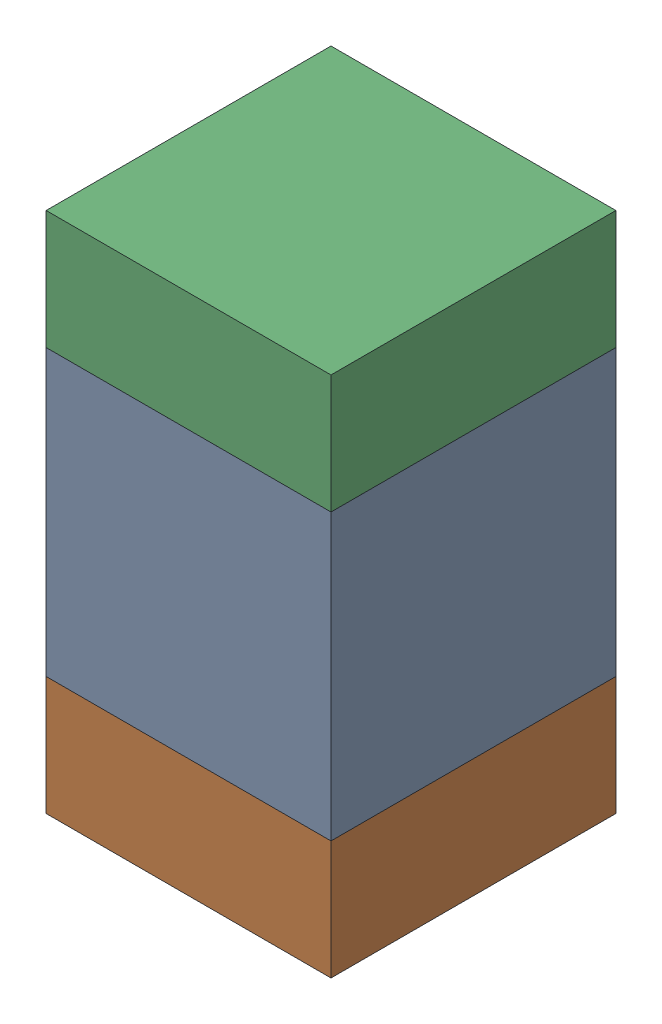
SolidWorks assembly C600_3PCB, configuration Default. Lengths in mm.
Overall size (0.6 1.1 0.6).
6 component instances, 2 part files, 0 mates.
Components (placement in the parent):
- 761606048-1: 761606048 [Default] at (100.6 96.05 -2.2638) size (0.6 0.6 0.6)
  - Extruded_9-1: Extruded_9 [Default] at origin size (0.6 0.6 0.6)
- 854785296-1: 854785296 [Default] at (100.6 95.625 -2.2638) size (0.6 0.25 0.6)
  - Extruded_10-1: Extruded_10 [Default] at origin size (0.6 0.25 0.6)
- 854785296-2: 854785296 [Default] at (100.6 96.475 -2.2638) size (0.6 0.25 0.6)
  - Extruded_10-1: Extruded_10 [Default] at origin size (0.6 0.25 0.6)
